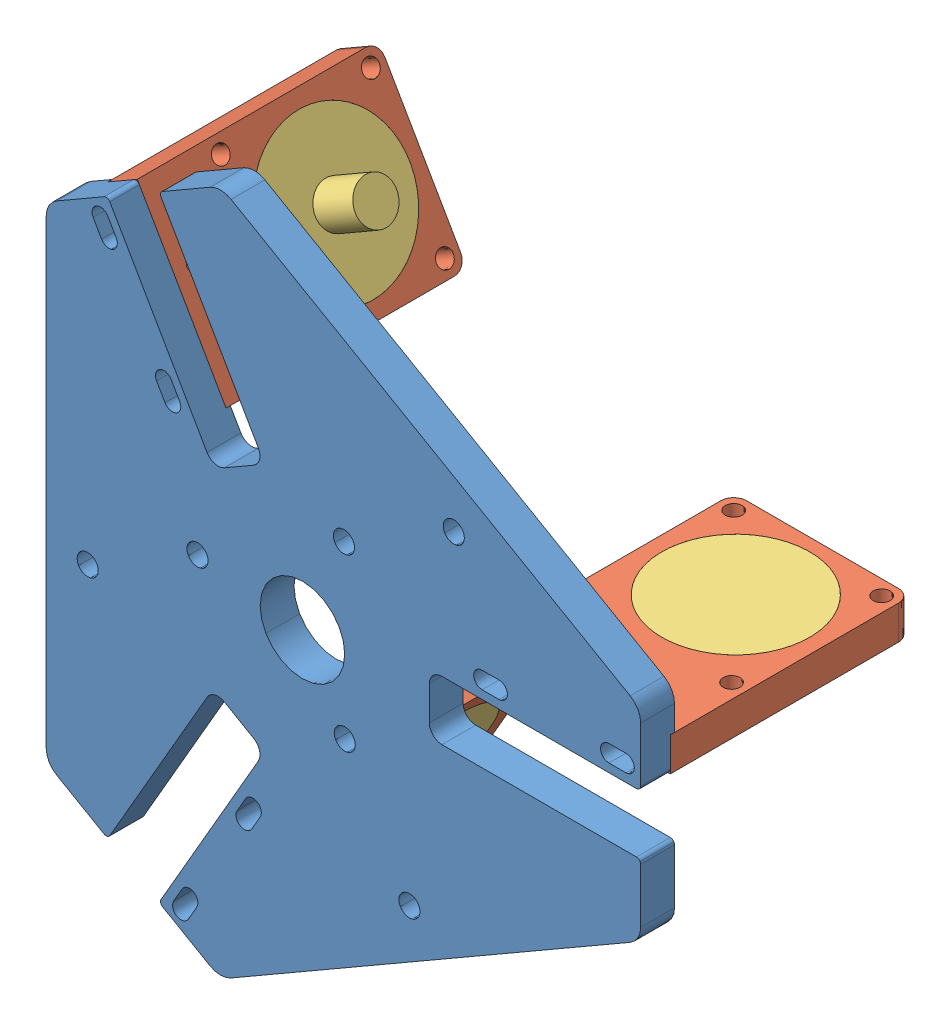
SolidWorks assembly Top_Delta_Simscape, configuration Default. Lengths in mm.
Overall size (143.84 160.83 67.72).
7 component instances, 3 part files, 16 mates.
Components (placement in the parent):
- BaseA_Simscape-1: BaseA_Simscape [Default] at origin size (140.62 160.83 8)
- PartARM-4: PartARM [Default] at (59 14.99 -27.5) x (0 0 -1) z (0 -1 0) size (57 42 8)
- PartARM-5: PartARM [Default] at (-23.437 -54.596 -27.5) x (0 0 -1) z (0.866025 -0.5 0) size (57 42 8)
- PartARM-6: PartARM [Default] at (-35.5701 47.5909 -27.5) x (0 0 -1) z (-0.866025 -0.5 0) size (57 42 8)
- Fake Motor-1: Fake Motor [Default] at (-16.5088 -58.596 -35.5) x (0.5 0.866025 0) z (-0.866025 0.5 0) size (35 35 18.9)
- Fake Motor-2: Fake Motor [Default] at (-42.4983 43.5909 -35.5) x (0.047628 -0.082495 0.995453) z (0.866025 0.5 0) size (35 35 18.9)
- Fake Motor-3: Fake Motor [Default] at (59 14.99 -35.5) x (-0.837169 0 -0.546944) z (0 -1 0) size (35 35 18.9)
Mates (geometry in assembly coordinates):
- Coincident1: coordinate: point of BaseA_Simscape-1
- Coincident2: coincident: plane of BaseA_Simscape-1 through (40.25 14.99 1) normal (0 0 -1); plane of PartARM-4 through (38 6.99 1) normal (0 0 1)
- Coincident3: coincident: plane of BaseA_Simscape-1 through (38 11.99 1) normal (1 0 0); plane of PartARM-4 through (38 6.99 1) normal (-1 0 0)
- Coincident4: coincident anti-aligned: plane of BaseA_Simscape-1 through (80 14.99 1) normal (0 -1 0); plane of PartARM-4 through (59 14.99 -27.5) normal (0 1 0)
- Coincident5: coincident: plane of BaseA_Simscape-1 through (-7.1338 -42.358 1) normal (0 0 -1); plane of PartARM-5 through (-27.0088 -76.7825 1) normal (0 0 1)
- Coincident6: coincident: plane of BaseA_Simscape-1 through (-8.6069 -38.9094 1) normal (-0.5 -0.866025 0); plane of PartARM-5 through (-6.0088 -40.4094 1) normal (0.5 0.866025 0)
- Coincident7: coincident anti-aligned: plane of BaseA_Simscape-1 through (-27.0088 -76.7825 1) normal (-0.866025 0.5 0); plane of PartARM-5 through (-16.5088 -58.596 -27.5) normal (0.866025 -0.5 0)
- Coincident8: coincident: plane of BaseA_Simscape-1 through (-33.1233 27.353 1) normal (0 0 -1); plane of PartARM-6 through (-52.9983 61.7775 1) normal (0 0 1)
- Coincident9: coincident: plane of BaseA_Simscape-1 through (-29.4002 26.9044 1) normal (-0.5 0.866025 0); plane of PartARM-6 through (-31.9983 25.4044 1) normal (0.5 -0.866025 0)
- Coincident10: coincident anti-aligned: plane of BaseA_Simscape-1 through (-52.9983 61.7775 1) normal (0.866025 0.5 0); plane of PartARM-6 through (-42.4983 43.5909 -27.5) normal (-0.866025 -0.5 0)
- Concentric1: concentric: cylinder of PartARM-5 through (-23.437 -54.596 -35.5) axis (0.866025 -0.5 0) radius 17.5; cylinder of Fake Motor-1 through (-23.437 -54.596 -35.5) axis (0.866025 -0.5 0) radius 17.5
- Coincident11: coincident aligned: plane of PartARM-5 through (-16.5088 -58.596 -27.5) normal (0.866025 -0.5 0); plane of Fake Motor-1 through (-16.5088 -58.596 -35.5) normal (0.866025 -0.5 0)
- Concentric2: concentric: cylinder of PartARM-4 through (59 14.99 -35.5) axis (0 -1 0) radius 17.5; cylinder of Fake Motor-3 through (59 6.99 -35.5) axis (0 1 0) radius 17.5
- Coincident12: coincident aligned: plane of PartARM-4 through (59 14.99 -27.5) normal (0 1 0); plane of Fake Motor-3 through (59 14.99 -35.5) normal (0 1 0)
- Concentric3: concentric: cylinder of PartARM-6 through (-35.5701 47.5909 -35.5) axis (-0.866025 -0.5 0) radius 17.5; cylinder of Fake Motor-2 through (-35.5701 47.5909 -35.5) axis (-0.866025 -0.5 0) radius 17.5
- Coincident13: coincident aligned: plane of PartARM-6 through (-42.4983 43.5909 -27.5) normal (-0.866025 -0.5 0); plane of Fake Motor-2 through (-42.4983 43.5909 -35.5) normal (-0.866025 -0.5 0)
